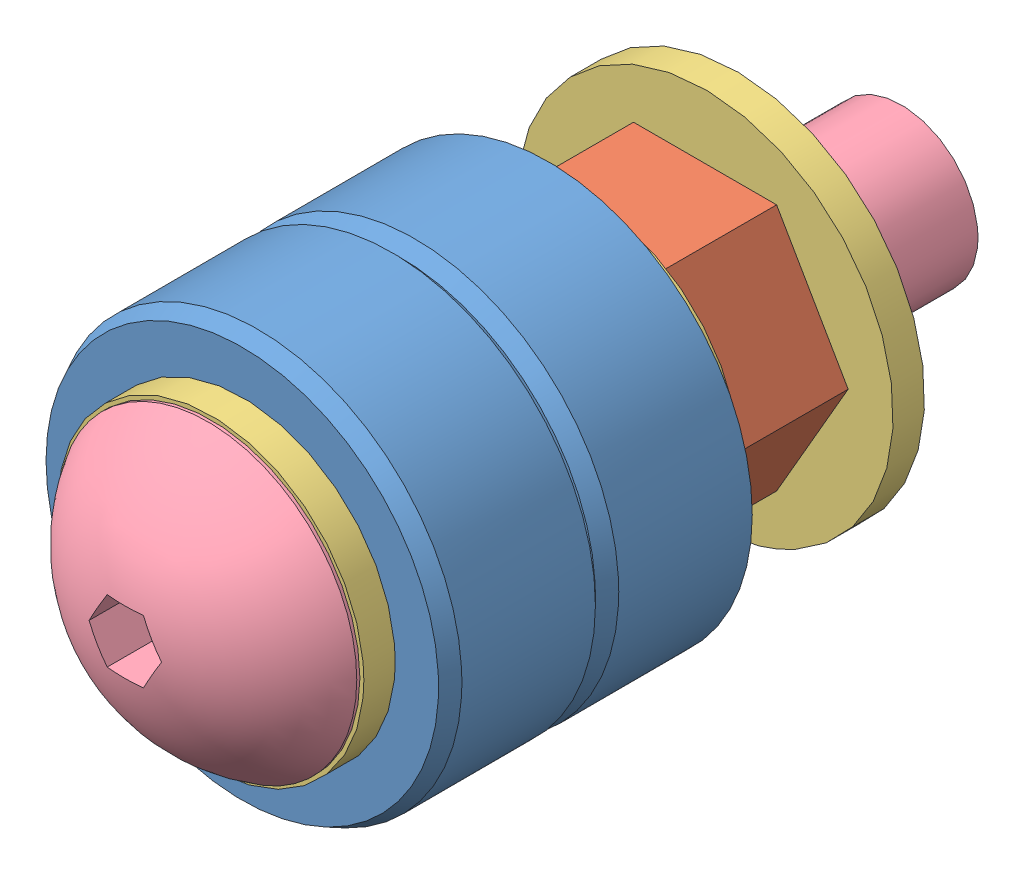
SolidWorks assembly Spectra Idler, configuration Default. Lengths in mm.
Overall size (15.69 15.69 24.76).
7 component instances, 4 part files, 12 mates.
Components (placement in the parent):
- 624ZZ-1: 624ZZ [Default] at origin size (13 13 5)
- 624ZZ-2: 624ZZ [Default] at (0 0 5) size (13 13 5)
- Nut-1: Nut [M5] at (0 0 -4.75) size (9.12 7.9 3.75)
- Washer-1: Washer [M5] at (0 0 10) size (9.75 9.75 1)
- Washer-2: Washer [M5] at (0 0 -1) size (9.75 9.75 1)
- Washer-3: Washer [M5 Fender] at (0 0 -5.75) x (0.384822 -0.922991 0) z (0 0 1) size (12 12 1)
- Button Head Screw-1: Button Head Screw [M5 x 22] at (0 0 -11) size (9.5 9.5 24.76)
Mates (geometry in assembly coordinates):
- Coincident1: coincident anti-aligned: plane of 624ZZ-1 through (0 0 5) normal (0 0 1); plane of 624ZZ-2 through (0 0 5) normal (0 0 -1)
- Concentric1: concentric aligned: cylinder of 624ZZ-1 through (0 0 5) axis (0 0 -1) radius 2; cylinder of 624ZZ-2 through (0 0 10) axis (0 0 -1) radius 2
- Concentric2: concentric aligned: cylinder of 624ZZ-2 through (0 0 10) axis (0 0 -1) radius 2; cylinder of Washer-1 through (0 0 11) axis (0 0 -1) radius 2.75
- Coincident2: coincident anti-aligned: plane of 624ZZ-2 through (0 0 10) normal (0 0 1); plane of Washer-1 through (0 0 10) normal (0 0 -1)
- Concentric3: concentric aligned: cylinder of 624ZZ-1 through (0 0 5) axis (0 0 -1) radius 2; cylinder of Washer-2 through (0 0 0) axis (0 0 -1) radius 2.75
- Coincident3: coincident anti-aligned: plane of 624ZZ-1 through (0 0 0) normal (0 0 -1); plane of Washer-2 through (0 0 0) normal (0 0 1)
- Concentric4: concentric anti-aligned: cylinder of 624ZZ-1 through (0 0 5) axis (0 0 -1) radius 2; cylinder of Nut-1 through (0 0 -4.75) axis (0 0 1) radius 2.25
- Coincident4: coincident anti-aligned: plane of Nut-1 through (2.2805 3.95 -1) normal (0 0 1); plane of Washer-2 through (0 0 -1) normal (0 0 -1)
- Concentric5: concentric aligned: cylinder of 624ZZ-1 through (0 0 5) axis (0 0 -1) radius 2; cylinder of Washer-3 through (0 0 -4.75) axis (0 0 -1) radius 2.75
- Coincident5: coincident anti-aligned: plane of Nut-1 through (2.2805 3.95 -4.75) normal (0 0 -1); plane of Washer-3 through (0 0 -4.75) normal (0 0 1)
- Coincident6: coincident anti-aligned: plane of Washer-1 through (0 0 11) normal (0 0 1); plane of Button Head Screw-1 through (0 0 11) normal (0 0 -1)
- Concentric6: concentric aligned: cylinder of 624ZZ-1 through (0 0 5) axis (0 0 -1) radius 2; cylinder of Button Head Screw-1 through (0 0 11) axis (0 0 -1) radius 2.45
